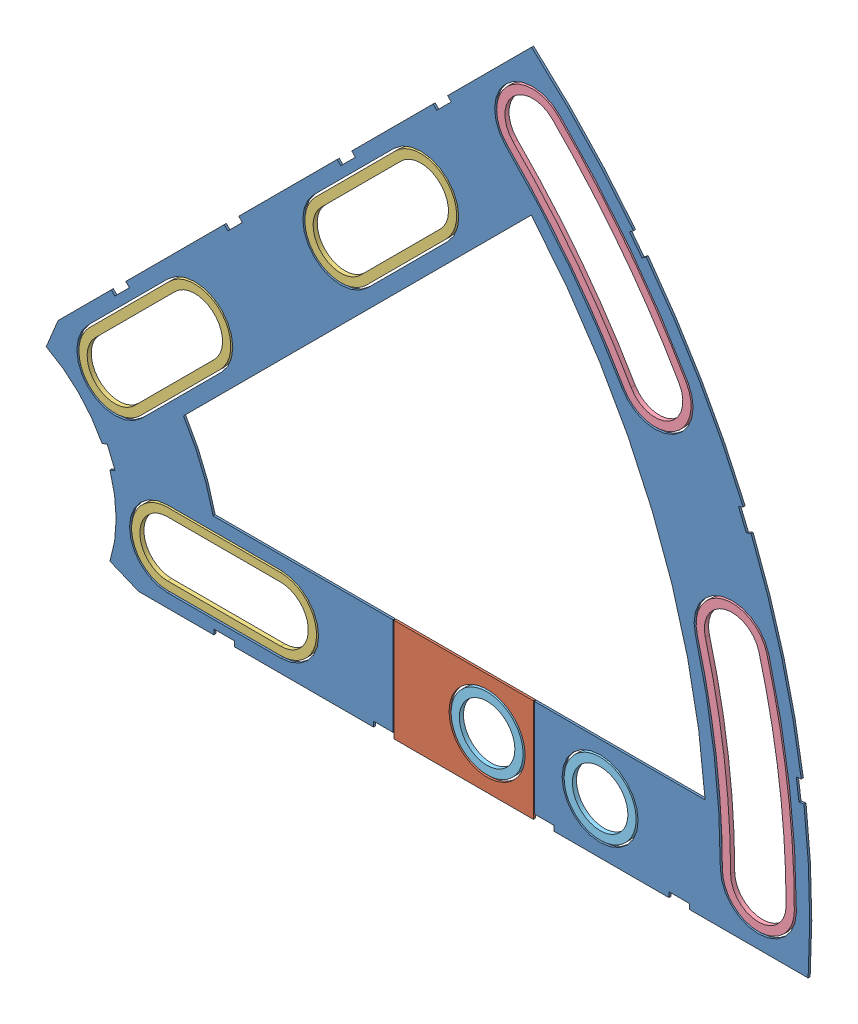
SolidWorks assembly Clover_10_Insul+Pass, configuration Default. Lengths in mm.
Overall size (96.6 82.54 0.51).
9 component instances, 5 part files, 22 mates.
Components (placement in the parent):
- Clover_10_Insul-1: Clover_10_Insul [Default] at (-18.0638 19.4773 68.2185) size (94.37 82.54 0.25)
- Clover_10_Pass-1: Clover_10_Pass [Default] at (-18.0638 19.4773 68.2185) size (17.21 12.7 0.25)
- Clover_Short_Washer-1: Clover_Short_Washer [Default] at (2.5908 40.1319 68.4725) x (0.707107 0.707107 0) z (-0.707107 0.707107 0) size (22.86 0.51 8.89)
- Clover_Short_Washer-2: Clover_Short_Washer [Default] at (30.5194 68.0605 68.4725) x (0.707107 0.707107 0) z (-0.707107 0.707107 0) size (22.86 0.51 8.89)
- Clover_Short_Washer-3: Clover_Short_Washer [Default] at (11.1462 19.4773 68.4725) x (1 0 0) z (0 1 0) size (22.86 0.51 8.89)
- Clover_Outside_Washer-1: Clover_Outside_Washer [Default] at (-18.0638 19.4773 68.4725) x (0.707107 0.707107 0) z (-0.707107 0.707107 0) size (12.14 0.51 33.54)
- Clover_Outside_Washer-2: Clover_Outside_Washer [Default] at (-18.0638 19.4773 68.4725) x (0.965926 0.258819 0) z (-0.258819 0.965926 0) size (12.14 0.51 33.54)
- Round_Washer-1: Round_Washer [Default] at (43.6582 19.4773 68.4725) x (1 0 0) z (0 1 0) size (8.89 0.51 8.89)
- Round_Washer-2: Round_Washer [Default] at (57.6282 19.4773 68.4725) x (1 0 0) z (0 1 0) size (8.89 0.51 8.89)
Mates (geometry in assembly coordinates):
- Coincident1: coincident: plane of Clover_10_Insul-1 through (-18.0638 19.4773 68.4725) normal (0 0 1); plane of Clover_10_Pass-1 through (-18.0638 19.4773 68.4725) normal (0 0 1)
- Coincident3: coincident: plane of Clover_10_Insul-1 through (70.6091 25.8273 68.4725) normal (0 1 0); plane of Clover_10_Pass-1 through (70.6091 25.8273 68.4725) normal (0 1 0)
- Distance1: distance = 2.54 mm: plane of Clover_10_Insul-1 through (29.6247 13.1273 68.2185) normal (1 0 0); plane of Clover_10_Pass-1 through (32.1647 13.1273 68.2185) normal (-1 0 0)
- Concentric1: concentric: circle of Clover_10_Pass-1; circle of Round_Washer-1
- Coincident4: coincident: plane of Clover_10_Pass-1 through (-18.0638 19.4773 68.4725) normal (0 0 1); plane of Round_Washer-1 through (43.6582 19.4773 68.4725) normal (0 0 1)
- Concentric2: concentric: circle of Clover_10_Insul-1; circle of Round_Washer-2
- Coincident5: coincident: plane of Clover_10_Insul-1 through (-18.0638 19.4773 68.4725) normal (0 0 1); plane of Round_Washer-2 through (57.6282 19.4773 68.4725) normal (0 0 1)
- Concentric3: concentric: circle of Clover_10_Insul-1; circle of Clover_Outside_Washer-2
- Concentric4: concentric: circle of Clover_10_Insul-1; circle of Clover_Outside_Washer-2
- Coincident6: coincident: plane of Clover_10_Insul-1 through (-18.0638 19.4773 68.4725) normal (0 0 1); plane of Clover_Outside_Washer-2 through (27.9384 31.8036 68.4725) normal (0 0 1)
- Concentric5: concentric: circle of Clover_10_Insul-1; circle of Clover_Outside_Washer-1
- Concentric6: concentric: circle of Clover_10_Insul-1; circle of Clover_Outside_Washer-1
- Coincident7: coincident: plane of Clover_10_Insul-1 through (-18.0638 19.4773 68.4725) normal (0 0 1); plane of Clover_Outside_Washer-1 through (15.6122 53.1533 68.4725) normal (0 0 1)
- Concentric7: concentric: circle of Clover_10_Insul-1; circle of Clover_Short_Washer-2
- Concentric8: concentric: circle of Clover_10_Insul-1; circle of Clover_Short_Washer-2
- Coincident8: coincident: plane of Clover_10_Insul-1 through (-18.0638 19.4773 68.4725) normal (0 0 1); plane of Clover_Short_Washer-2 through (25.5802 63.1214 68.4725) normal (0 0 1)
- Concentric9: concentric: circle of Clover_10_Insul-1; circle of Clover_Short_Washer-1
- Concentric10: concentric: circle of Clover_10_Insul-1; circle of Clover_Short_Washer-1
- Coincident9: coincident: plane of Clover_10_Insul-1 through (-18.0638 19.4773 68.4725) normal (0 0 1); plane of Clover_Short_Washer-1 through (-2.3484 35.1928 68.4725) normal (0 0 1)
- Concentric11: concentric: circle of Clover_10_Insul-1; circle of Clover_Short_Washer-3
- Concentric12: concentric: circle of Clover_10_Insul-1; circle of Clover_Short_Washer-3
- Coincident10: coincident: plane of Clover_10_Insul-1 through (-18.0638 19.4773 68.4725) normal (0 0 1); plane of Clover_Short_Washer-3 through (4.1612 19.4773 68.4725) normal (0 0 1)
